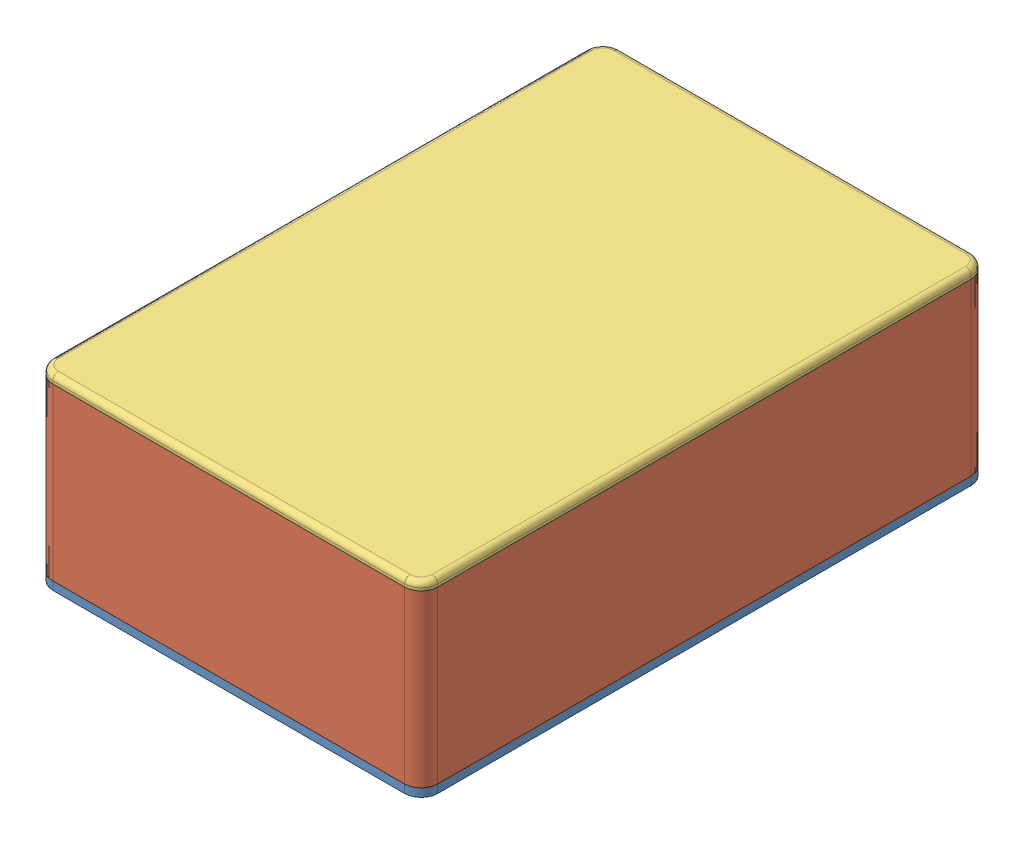
SolidWorks assembly Universal_case_assembly, configuration Default. Lengths in mm.
Overall size (69.96 34 102.98).
3 component instances, 3 part files, 7 mates.
Components (placement in the parent):
- Universal_case_base-1: Universal_case_base [Default] at origin size (69.96 9 102.98)
- Universal_case_sides-1: Universal_case_sides [Default] at (0 1.5 0) size (69.96 31 102.98)
- Universal_case_lid-1: Universal_case_lid [Default] at (0 34.0002 0) x (1 0 0) z (0 0 -1) size (69.96 4.35 102.98)
Mates (geometry in assembly coordinates):
- Coincident3: coordinate: point of Universal_case_base-1; point of assembly
- Coincident4: coincident: plane of Universal_case_base-1 through (0 1.5 0) normal (0 1 0); plane of Universal_case_sides-1 through (0 1.5 0) normal (0 -1 0)
- Coincident5: coincident: plane of Universal_case_sides-1 through (0 32.5002 0) normal (0 1 0); plane of Universal_case_lid-1 through (0 32.5002 0) normal (0 -1 0)
- Coincident6: coincident: plane of Universal_case_base-1 through (-34.98 1.5 51.49) normal (0 0 1); plane of Universal_case_sides-1 through (-34.98 32.5002 51.49) normal (0 0 1)
- Coincident7: coincident: plane of Universal_case_base-1 through (34.98 1.5 51.49) normal (1 0 0); plane of Universal_case_sides-1 through (34.98 32.5002 51.49) normal (1 0 0)
- Coincident8: coincident: plane of Universal_case_sides-1 through (-34.98 32.5002 51.49) normal (0 0 1); plane of Universal_case_lid-1 through (-34.98 32.5002 51.49) normal (0 0 1)
- Coincident9: coincident: plane of Universal_case_sides-1 through (34.98 32.5002 51.49) normal (1 0 0); plane of Universal_case_lid-1 through (34.98 32.5002 -51.49) normal (1 0 0)
